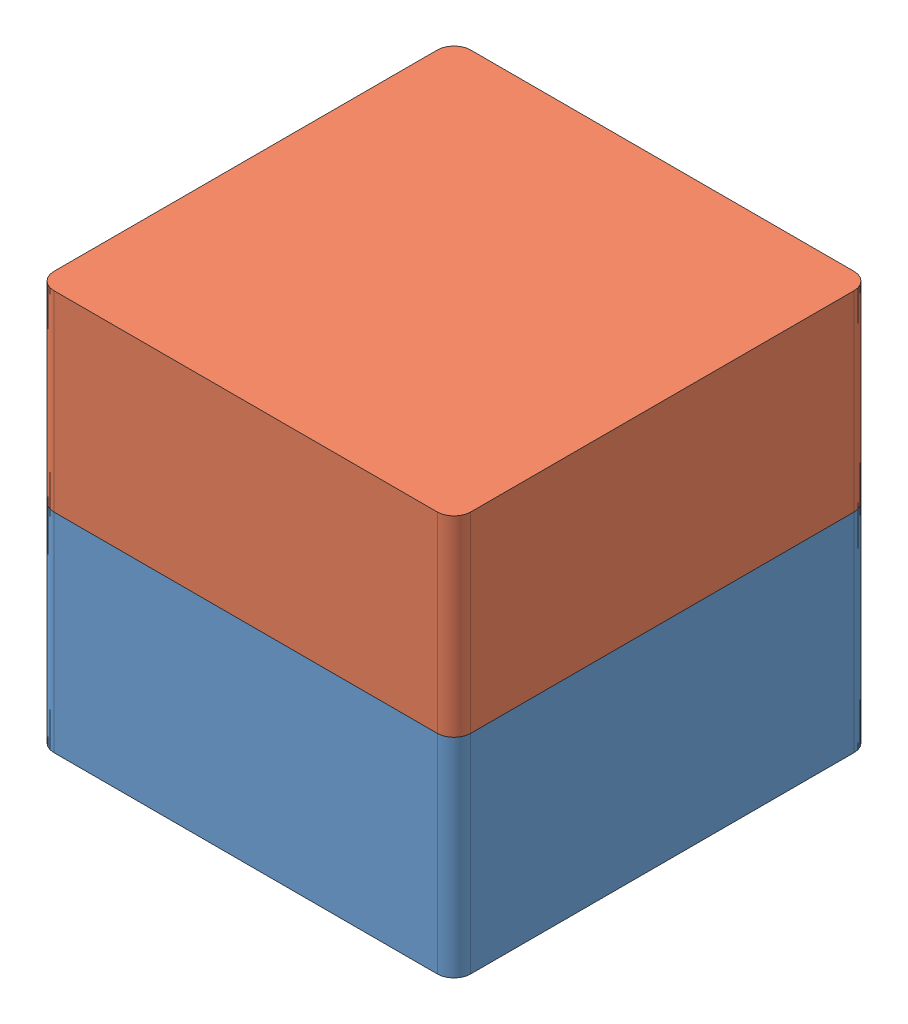
SolidWorks assembly serwo_zasuwa, configuration Domyślna. Lengths in mm.
Overall size (50 48 50).
2 component instances, 2 part files, 4 mates.
Components (placement in the parent):
- mocowanie_serwo_cz1-1: mocowanie_serwo_cz1 [Domyślna] at (-6.1439 -9.2784 50) size (50 25 50)
- mocowanie_serwo_cz2-1: mocowanie_serwo_cz2 [Domyślna] at (-6.1439 15.7216 50) x (1 0 0) z (0 1 0) size (50 50 25)
Mates (geometry in assembly coordinates):
- Ustalone2: in place: plane of mocowanie_serwo_cz1-1 through (-6.1439 11.7216 50) normal (0 1 0); plane of ? through (0 11.7216 0) normal (0 1 0); moOrthogonalPlaneRef_w of mocowanie_serwo_cz1-1 through (-6.1439 11.7216 50) normal (0 1 0); plane of ? through (0 11.7216 0) normal (0 0 -1); plane of mocowanie_serwo_cz1-1 through (-6.1439 11.7216 50) normal (0 1 0); plane of ? through (0 11.7216 0) normal (1 0 0); plane of mocowanie_serwo_cz1-1 through (-6.1439 15.7216 50) normal (0 1 0); unknown of mocowanie_serwo_cz2-1
- Wspólnie4: coincident aligned: plane of ?; plane of ?
- Wspólnie5: coincident aligned: moOrthogonalPlaneRef_w of mocowanie_serwo_cz1-1 through (-6.1439 15.7216 50) normal (0 0 -1); plane of Część3^Złożenie1-1 through (-6.1439 15.7216 50) normal (0 0 -1)
- Wspólnie6: coincident anti-aligned: moOrthogonalPlaneRef_w of mocowanie_serwo_cz1-1 through (-6.1439 15.7216 50) normal (-1 0 0); plane of Część3^Złożenie1-1 through (-6.1439 15.7216 50) normal (1 0 0)
